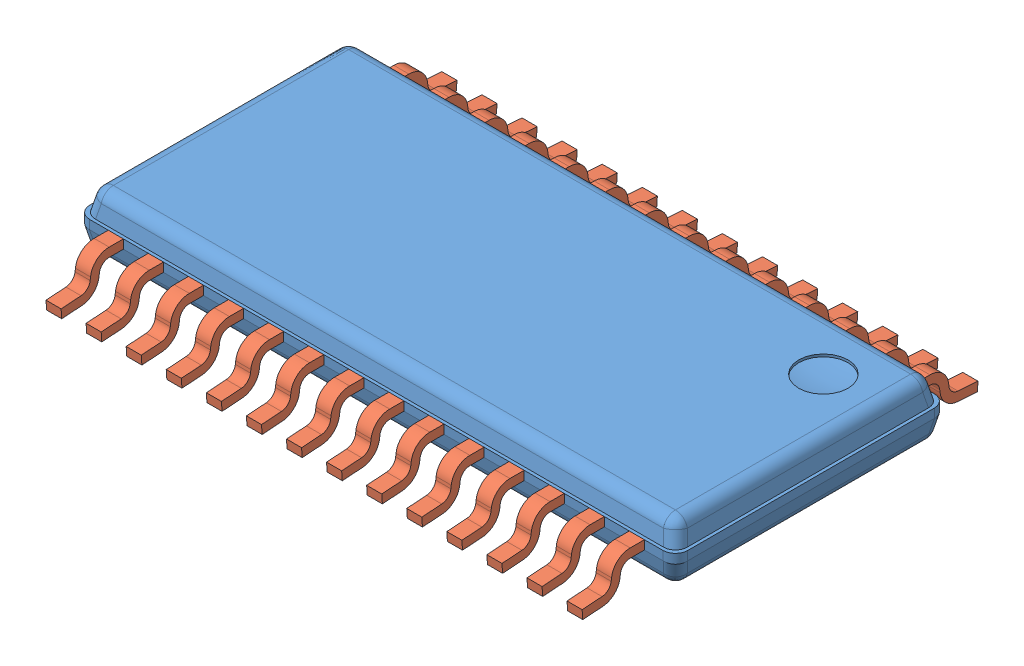
SolidWorks assembly PWP0028A, configuration Default. Lengths in mm.
Overall size (9.7 1.03 6.42).
29 component instances, 2 part files, 0 mates.
Components (placement in the parent):
- BODY_MXA28A-1: BODY_MXA28A [Default] at origin size (9.7 0.95 4.4)
- LEAD_MXA28A-1: LEAD_MXA28A [Default] at (4.225 -0.3725 -2.6) x (-1 0 0) z (0 0 -1) size (0.25 0.62 1.01)
- LEAD_MXA28A-2: LEAD_MXA28A [Default] at (3.575 -0.3725 -2.6) x (-1 0 0) z (0 0 -1) size (0.25 0.62 1.01)
- LEAD_MXA28A-3: LEAD_MXA28A [Default] at (2.925 -0.3725 -2.6) x (-1 0 0) z (0 0 -1) size (0.25 0.62 1.01)
- LEAD_MXA28A-4: LEAD_MXA28A [Default] at (2.275 -0.3725 -2.6) x (-1 0 0) z (0 0 -1) size (0.25 0.62 1.01)
- LEAD_MXA28A-5: LEAD_MXA28A [Default] at (1.625 -0.3725 -2.6) x (-1 0 0) z (0 0 -1) size (0.25 0.62 1.01)
- LEAD_MXA28A-6: LEAD_MXA28A [Default] at (0.975 -0.3725 -2.6) x (-1 0 0) z (0 0 -1) size (0.25 0.62 1.01)
- LEAD_MXA28A-7: LEAD_MXA28A [Default] at (0.325 -0.3725 -2.6) x (-1 0 0) z (0 0 -1) size (0.25 0.62 1.01)
- LEAD_MXA28A-8: LEAD_MXA28A [Default] at (-0.325 -0.3725 -2.6) x (-1 0 0) z (0 0 -1) size (0.25 0.62 1.01)
- LEAD_MXA28A-9: LEAD_MXA28A [Default] at (-0.975 -0.3725 -2.6) x (-1 0 0) z (0 0 -1) size (0.25 0.62 1.01)
- LEAD_MXA28A-10: LEAD_MXA28A [Default] at (-1.625 -0.3725 -2.6) x (-1 0 0) z (0 0 -1) size (0.25 0.62 1.01)
- LEAD_MXA28A-11: LEAD_MXA28A [Default] at (-2.275 -0.3725 -2.6) x (-1 0 0) z (0 0 -1) size (0.25 0.62 1.01)
- LEAD_MXA28A-12: LEAD_MXA28A [Default] at (-2.925 -0.3725 -2.6) x (-1 0 0) z (0 0 -1) size (0.25 0.62 1.01)
- LEAD_MXA28A-13: LEAD_MXA28A [Default] at (-3.575 -0.3725 -2.6) x (-1 0 0) z (0 0 -1) size (0.25 0.62 1.01)
- LEAD_MXA28A-14: LEAD_MXA28A [Default] at (-4.225 -0.3725 -2.6) x (-1 0 0) z (0 0 -1) size (0.25 0.62 1.01)
- LEAD_MXA28A-15: LEAD_MXA28A [Default] at (4.225 -0.3725 2.6) size (0.25 0.62 1.01)
- LEAD_MXA28A-16: LEAD_MXA28A [Default] at (3.575 -0.3725 2.6) size (0.25 0.62 1.01)
- LEAD_MXA28A-17: LEAD_MXA28A [Default] at (2.925 -0.3725 2.6) size (0.25 0.62 1.01)
- LEAD_MXA28A-18: LEAD_MXA28A [Default] at (2.275 -0.3725 2.6) size (0.25 0.62 1.01)
- LEAD_MXA28A-19: LEAD_MXA28A [Default] at (1.625 -0.3725 2.6) size (0.25 0.62 1.01)
- LEAD_MXA28A-20: LEAD_MXA28A [Default] at (0.975 -0.3725 2.6) size (0.25 0.62 1.01)
- LEAD_MXA28A-21: LEAD_MXA28A [Default] at (0.325 -0.3725 2.6) size (0.25 0.62 1.01)
- LEAD_MXA28A-22: LEAD_MXA28A [Default] at (-0.325 -0.3725 2.6) size (0.25 0.62 1.01)
- LEAD_MXA28A-23: LEAD_MXA28A [Default] at (-0.975 -0.3725 2.6) size (0.25 0.62 1.01)
- LEAD_MXA28A-24: LEAD_MXA28A [Default] at (-1.625 -0.3725 2.6) size (0.25 0.62 1.01)
- LEAD_MXA28A-25: LEAD_MXA28A [Default] at (-2.275 -0.3725 2.6) size (0.25 0.62 1.01)
- LEAD_MXA28A-26: LEAD_MXA28A [Default] at (-2.925 -0.3725 2.6) size (0.25 0.62 1.01)
- LEAD_MXA28A-27: LEAD_MXA28A [Default] at (-3.575 -0.3725 2.6) size (0.25 0.62 1.01)
- LEAD_MXA28A-28: LEAD_MXA28A [Default] at (-4.225 -0.3725 2.6) size (0.25 0.62 1.01)
